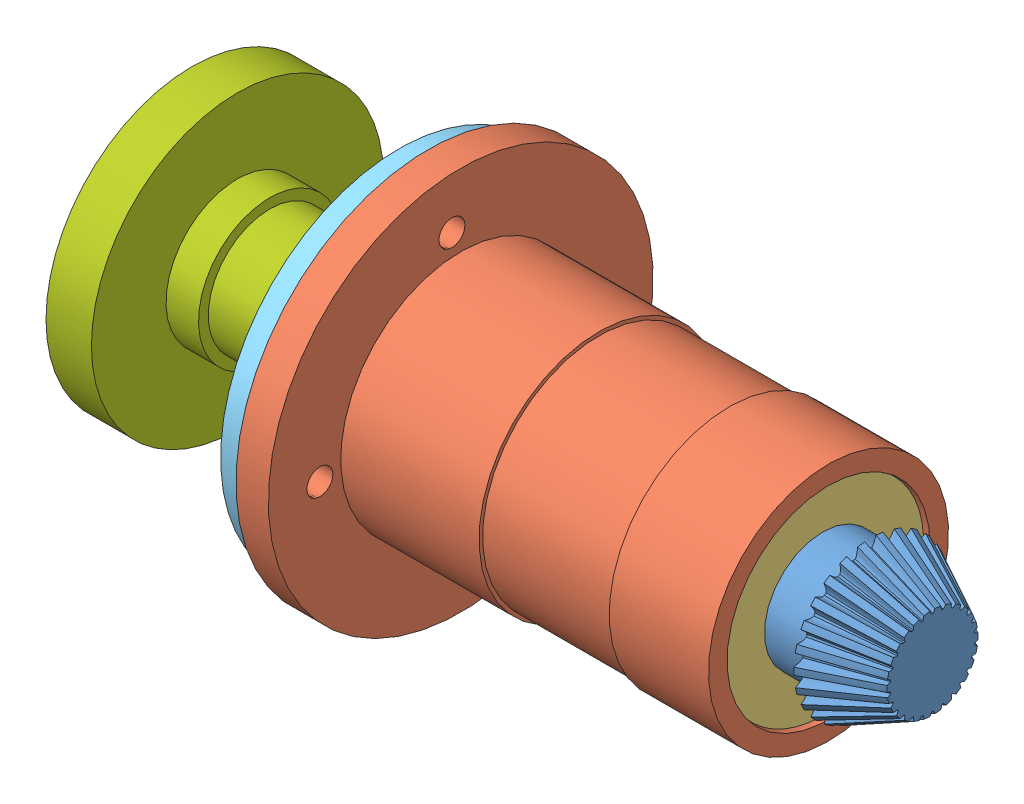
SolidWorks assembly 轴系, configuration 默认. Lengths in mm.
Overall size (228.22 125.78 125.78).
10 component instances, 9 part files, 20 mates.
Components (placement in the parent):
- 轴-1: 轴 [默认] at (18.6441 -37.9841 0) size (212.22 47.17 47.3)
- 衬套-1: 衬套 [默认] at (-3.9045 -9.8868 0) x (1 0 0) z (0 -0.062498 0.998045) size (123.36 118.6 118.6)
- 轴承-1: 轴承 [默认] at (58.5323 -9.8868 0) x (0 0 1) z (-1 0 0) size (62 62 17.25)
- 轴承-2: 轴承 [默认] at (-22.1177 -9.8868 0) x (0 -0.473975 0.880538) z (-1 0 0) size (62 62 17.25)
- 定位螺钉-1: 定位螺钉 [默认] at (-36.2164 -9.8868 0) size (6 39.9 39.9)
- 端盖-1: 端盖 [默认] at (-62.9664 -9.8868 0) x (1 0 0) z (0 -0.054029 0.998539) size (30.96 110 110)
- 键-1: 键 [默认] at (-98.7964 -9.8868 8) size (19 5 5)
- 联轴器-1: 联轴器 [默认] at (-126.7964 -9.8868 0) x (1 0 0) z (0 -1 0) size (40 90 90)
- 垫片-1: 垫片 [默认] at (-118.7964 -9.8868 0) size (4 30 30)
- 螺钉-1: 螺钉 [默认] at (-123.7964 -9.8868 0) size (25 13.01 15.01)
Mates (geometry in assembly coordinates):
- 同心1: concentric anti-aligned: cylinder of 轴-1 through (101.4236 -9.8868 0) axis (1 0 0) radius 14.37; cylinder of 轴承-1 through (31.1633 -9.8868 0) axis (-1 0 0) radius 15
- 重合1: coincident anti-aligned: plane of 轴-1 through (67.6836 4.9732 0) normal (-1 0 0); plane of 轴承-1 through (67.6836 -4.335 0) normal (1 0 0)
- 同心2: concentric aligned: cylinder of 衬套-1 through (-70.9477 -9.8868 0) axis (-1 0 0) radius 31.28; cylinder of 轴承-1 through (31.1633 -9.8868 0) axis (-1 0 0) radius 31
- 重合2: coincident anti-aligned: plane of 衬套-1 through (50.4336 19.336 1.8299) normal (1 0 0); plane of 轴承-1 through (50.4336 -4.335 0) normal (-1 0 0)
- 同心3: concentric anti-aligned: cylinder of 轴-1 through (101.4236 -9.8868 0) axis (1 0 0) radius 14.86; cylinder of 轴承-2 through (-49.4867 -9.8868 0) axis (-1 0 0) radius 15
- 重合3: coincident anti-aligned: plane of 衬套-1 through (-12.9664 21.3321 1.9549) normal (-1 0 0); plane of 轴承-2 through (-12.9664 -4.9982 2.6314) normal (1 0 0)
- 同心4: concentric anti-aligned: cylinder of 轴-1 through (101.4236 -9.8868 0) axis (1 0 0) radius 15; cylinder of 定位螺钉-1 through (-30.2164 -9.8868 0) axis (-1 0 0) radius 15
- 重合4: coincident anti-aligned: plane of 轴承-2 through (-30.2164 -4.9982 2.6314) normal (-1 0 0); plane of 定位螺钉-1 through (-30.2164 -9.8868 -44.1414) normal (1 0 0)
- 同心5: concentric aligned: cylinder of 衬套-1 through (-70.9477 -9.8868 0) axis (-1 0 0) radius 31.28; cylinder of 端盖-1 through (-32.0064 -9.8868 0) axis (-1 0 0) radius 30.95
- 重合5: coincident anti-aligned: plane of 衬套-1 through (-53.9664 49.2976 3.7061) normal (-1 0 0); plane of 端盖-1 through (-53.9664 -9.8868 0) normal (1 0 0)
- 重合6: coincident anti-aligned: plane of 轴-1 through (-98.7964 -28.6958 8) normal (0 0 1); plane of 键-1 through (-98.7964 -25.3099 8) normal (0 0 -1)
- 重合7: coincident anti-aligned: plane of 轴-1 through (-98.7964 -7.3868 18) normal (0 -1 0); plane of 键-1 through (-98.7964 -7.3868 13) normal (0 1 0)
- 同心6: concentric aligned: cylinder of 轴-1 through (-91.7964 -9.8868 18) axis (0 0 -1) radius 2.5; cylinder of 键-1 through (-91.7964 -9.8868 13) axis (0 0 -1) radius 2.5
- 重合8: coincident anti-aligned: plane of 键-1 through (-98.7964 -12.3868 13) normal (0 -1 0); plane of 联轴器-1 through (-86.7964 -12.3868 0) normal (0 1 0)
- 重合9: coincident anti-aligned: plane of 轴-1 through (-86.7964 0.5632 0) normal (-1 0 0); plane of 联轴器-1 through (-86.7964 -9.8868 0) normal (1 0 0)
- 同心7: concentric anti-aligned: circle of 轴-1; cylinder of 联轴器-1 through (-86.7964 -9.8868 0) axis (-1 0 0) radius 11
- 重合11: coincident anti-aligned: plane of 联轴器-1 through (-114.7964 -9.8868 0) normal (-1 0 0); plane of 垫片-1 through (-114.7964 -9.8868 0) normal (1 0 0)
- 同心8: concentric aligned: cylinder of 联轴器-1 through (-86.7964 -9.8868 0) axis (-1 0 0) radius 11; cylinder of 垫片-1 through (-114.7964 -9.8868 0) axis (-1 0 0) radius 5
- 同心10: concentric aligned: cylinder of 垫片-1 through (-114.7964 -9.8868 0) axis (-1 0 0) radius 5; cylinder of 螺钉-1 through (-98.7964 -9.8868 0) axis (-1 0 0) radius 5
- 重合12: coincident anti-aligned: plane of 垫片-1 through (-118.7964 -9.8868 0) normal (-1 0 0); plane of 螺钉-1 through (-118.7964 -16.3801 -3.7643) normal (1 0 0)
